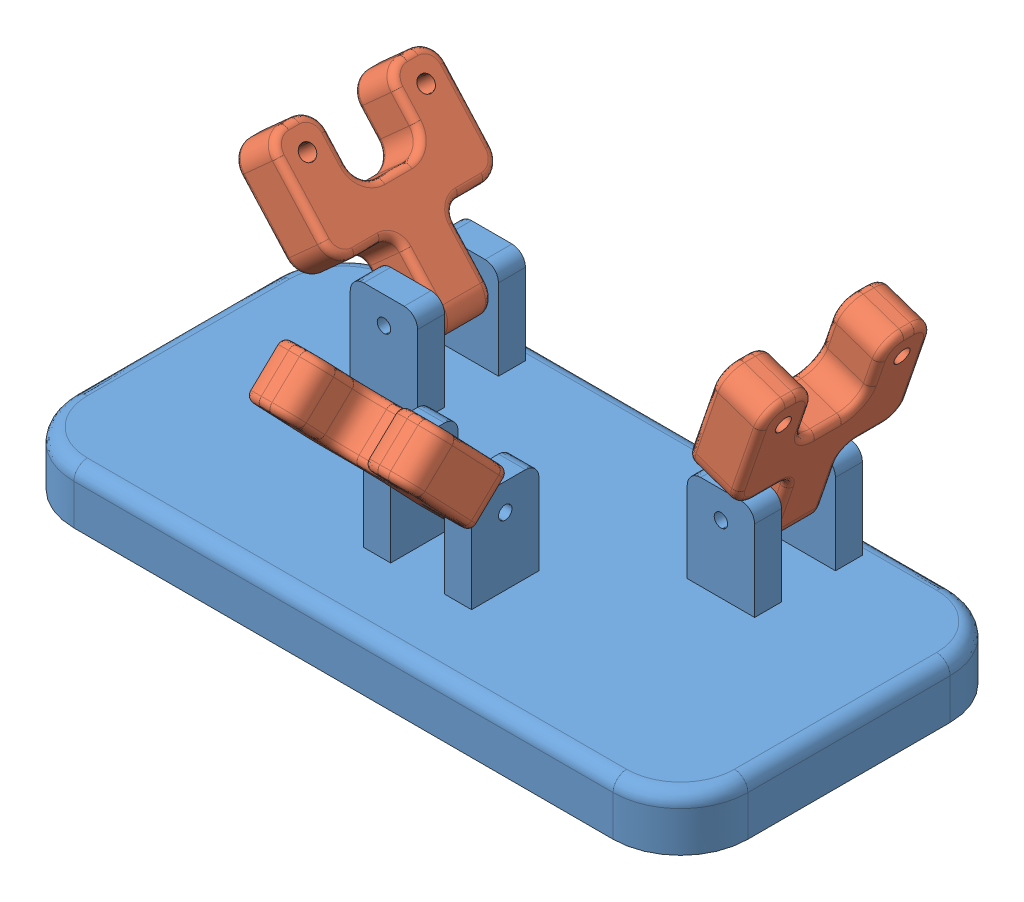
SolidWorks assembly bluefeet, configuration Default. Lengths in mm.
Overall size (100 41.94 54.92).
4 component instances, 2 part files, 9 mates.
Components (placement in the parent):
- feet-1: feet [Default] at origin size (100 22 50)
- link2-1: link2 [Default] at (-26.3367 19.4877 -14) x (0 0 -1) z (0.743848 0.668349 0) size (25.2 28 7.6)
- link2-2: link2 [Default] at (0 19.4468 10.3809) x (1 0 0) z (0 -0.690435 0.723395) size (25.2 28 7.6)
- link2-3: link2 [Default] at (25.6464 19.8927 -14) x (0 0 -1) z (0.94633 -0.323202 0) size (25.2 28 7.6)
Mates (geometry in assembly coordinates):
- Coincident1: coincident anti-aligned: plane of feet-1 through (40 0 15) normal (0 -1 0)
- Distance1: distance = 25 mm aligned: plane of feet-1 through (-40 8 25) normal (0 0 1)
- Distance2: distance = 50 mm aligned: plane of feet-1 through (50 8 -15) normal (1 0 0)
- Concentric1: concentric anti-aligned: cylinder of feet-1 through (-25 18 -22) axis (0 0 1) radius 1; cylinder of link2-1 through (-25 18 -10.2) axis (0 0 -1) radius 1.15
- Distance3: distance = 0.2 mm anti-aligned: plane of link2-1 through (-29.1633 16.948 -17.8) normal (0 0 -1); plane of feet-1 through (-30 22 -18) normal (0 0 1)
- Concentric2: concentric anti-aligned: cylinder of feet-1 through (8 18 9) axis (-1 0 0) radius 1; cylinder of link2-2 through (-3.8 18 9) axis (1 0 0) radius 1.15
- Distance4: distance = 0.2 mm anti-aligned: plane of link2-2 through (3.8 22.0704 7.632) normal (1 0 0); plane of feet-1 through (4 22 4) normal (-1 0 0)
- Concentric3: concentric anti-aligned: cylinder of feet-1 through (25 18 -22) axis (0 0 1) radius 1; cylinder of link2-3 through (25 18 -10.2) axis (0 0 -1) radius 1.15
- Distance5: distance = 0.2 mm anti-aligned: plane of link2-3 through (22.0503 21.1208 -10.2) normal (0 0 1); plane of feet-1 through (30 22 -10) normal (0 0 -1)
